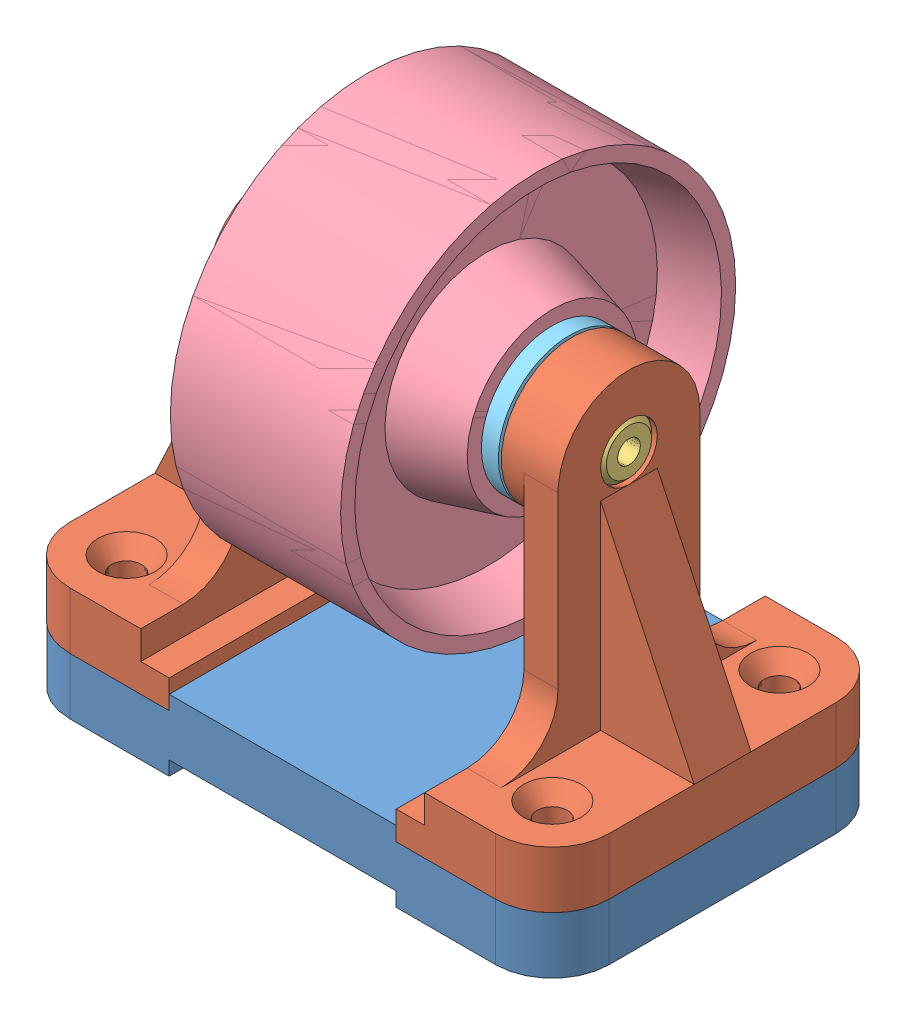
SolidWorks assembly WheelAssem, configuration Default. Lengths in mm.
Overall size (120.65 133.23 114.06).
7 component instances, 5 part files, 17 mates.
Components (placement in the parent):
- partPart3-1: partPart3 [Default] at origin size (120.65 15.88 76.2)
- partPart2-1: partPart2 [Default] at (14.0758 12.7 -38.1) x (0 0 -1) z (1 0 0) size (76.2 79.38 34.92)
- partPart2-2: partPart2 [Default] at (99.8008 12.7 -38.1) x (0 0 1) z (-1 0 0) size (76.2 79.38 34.92)
- partPart4-1: partPart4 [Default] at (56.9383 76.2 -38.1) x (0 1 0) z (1 0 0) size (17.14 17.14 78.74)
- partPart1-2: partPart1 [Default] at (55.6625 76.2 -38.1) x (0 0.934535 -0.355872) z (0 0.355872 0.934535) size (88.39 44.45 88.39)
- partPart5-1: partPart5 [Default] at (79.1633 76.2 -38.1) x (0 0 -1) z (1 0 0) size (31.75 31.75 22.86)
- partPart5-2: partPart5 [Default] at (34.7133 76.2 -38.1) x (0 0 1) z (-1 0 0) size (31.75 31.75 22.86)
Mates (geometry in assembly coordinates):
- Coincident2: coincident: plane of partPart3-1 through (0 0 0) normal (0 0 1); plane of assembly through (0 0 0) normal (0 0 1)
- Coincident3: coincident: plane of partPart3-1 through (0 0 0) normal (0 1 0); plane of assembly through (0 0 0) normal (0 1 0)
- Coincident4: coincident: plane of partPart3-1 through (0 0 0) normal (1 0 0); plane of assembly through (0 0 0) normal (1 0 0)
- Coincident5: coincident: plane of partPart3-1 through (117.2633 12.7 -76.2) normal (0 1 0); plane of partPart2-2 through (104.5633 12.7 -12.7) normal (0 -1 0)
- Coincident7: coincident: plane of partPart3-1 through (0 0 -76.2) normal (0 0 -1); plane of partPart2-2 through (104.5633 25.4 -76.2) normal (0 0 -1)
- Coincident8: coincident: plane of partPart3-1 through (117.2633 0 -76.2) normal (1 0 0); plane of partPart2-2 through (117.2633 25.4 -63.5) normal (1 0 0)
- Coincident9: coincident: plane of partPart3-1 through (31.5383 12.7 -76.2) normal (0 1 0); plane of partPart2-1 through (9.3133 12.7 -63.5) normal (0 -1 0)
- Coincident10: coincident: plane of partPart3-1 through (0 0 -76.2) normal (0 0 -1); plane of partPart2-1 through (9.3133 25.4 -76.2) normal (0 0 -1)
- Coincident11: coincident: plane of partPart3-1 through (-3.3867 12.7 -76.2) normal (-1 0 0); plane of partPart2-1 through (-3.3867 25.4 -12.7) normal (-1 0 0)
- Coincident12: coincident: plane of partPart2-1 through (17.5683 76.2 -38.1) normal (-1 0 0); plane of partPart4-1 through (17.5683 76.2 -38.1) normal (-1 0 0)
- Concentric1: concentric: cylinder of partPart2-1 through (30.2683 76.2 -38.1) axis (-1 0 0) radius 6.35; cylinder of partPart4-1 through (96.3083 76.2 -38.1) axis (-1 0 0) radius 6.35
- Concentric2: concentric: cylinder of partPart4-1 through (83.6083 76.2 -38.1) axis (-1 0 0) radius 8.5725; cylinder of partPart1-2 through (12.9311 76.2 -38.1) axis (-1 0 0) radius 12.7
- Width1: width: plane of partPart2-1 through (30.2683 76.2 -38.1) normal (1 0 0); plane of partPart2-2 through (83.6083 76.2 -38.1) normal (-1 0 0); plane of partPart1-2 through (34.7133 88.0686 -42.6196) normal (-1 0 0); plane of partPart1-2 through (79.1633 94.0029 -44.8794) normal (1 0 0)
- Concentric3: concentric: cylinder of partPart1-2 through (12.9311 76.2 -38.1) axis (-1 0 0) radius 12.7; cylinder of partPart5-2 through (53.7633 76.2 -38.1) axis (-1 0 0) radius 12.7
- Coincident14: coincident: plane of partPart1-2 through (34.7133 88.0686 -42.6196) normal (-1 0 0); plane of partPart5-2 through (34.7133 76.2 -38.1) normal (1 0 0)
- Concentric4: concentric: cylinder of partPart1-2 through (12.9311 76.2 -38.1) axis (-1 0 0) radius 12.7; cylinder of partPart5-1 through (60.1133 76.2 -38.1) axis (1 0 0) radius 12.7
- Coincident15: coincident: plane of partPart1-2 through (79.1633 94.0029 -44.8794) normal (1 0 0); plane of partPart5-1 through (79.1633 76.2 -38.1) normal (-1 0 0)
